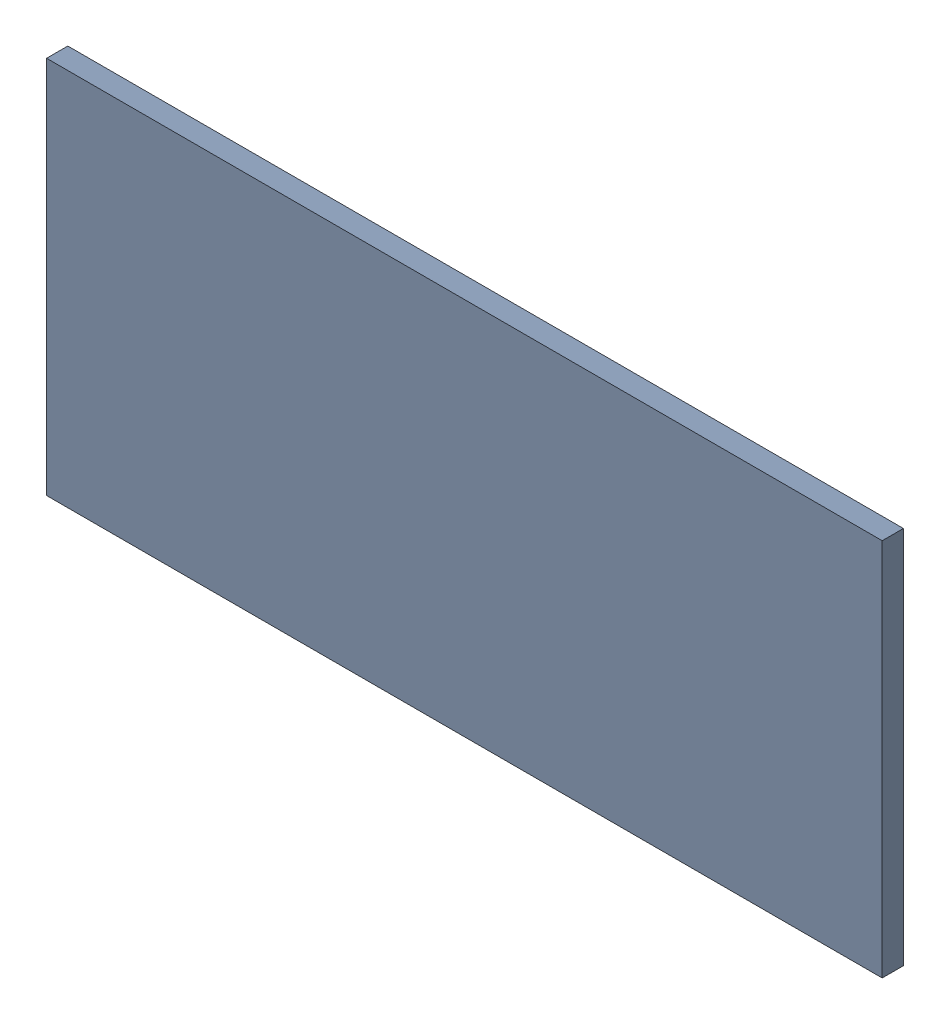
SolidWorks assembly 6327400576, configuration Default. Lengths in mm.
Overall size (1 0.45 0.03).
2 component instances, 1 part files, 0 mates.
Components (placement in the parent):
- 6701982208-1:  [Default] at (27.7 14.8 0) (suppressed, hidden)
- Extruded-25-1: Extruded-25 [Default] at origin size (1 0.45 0.03)
